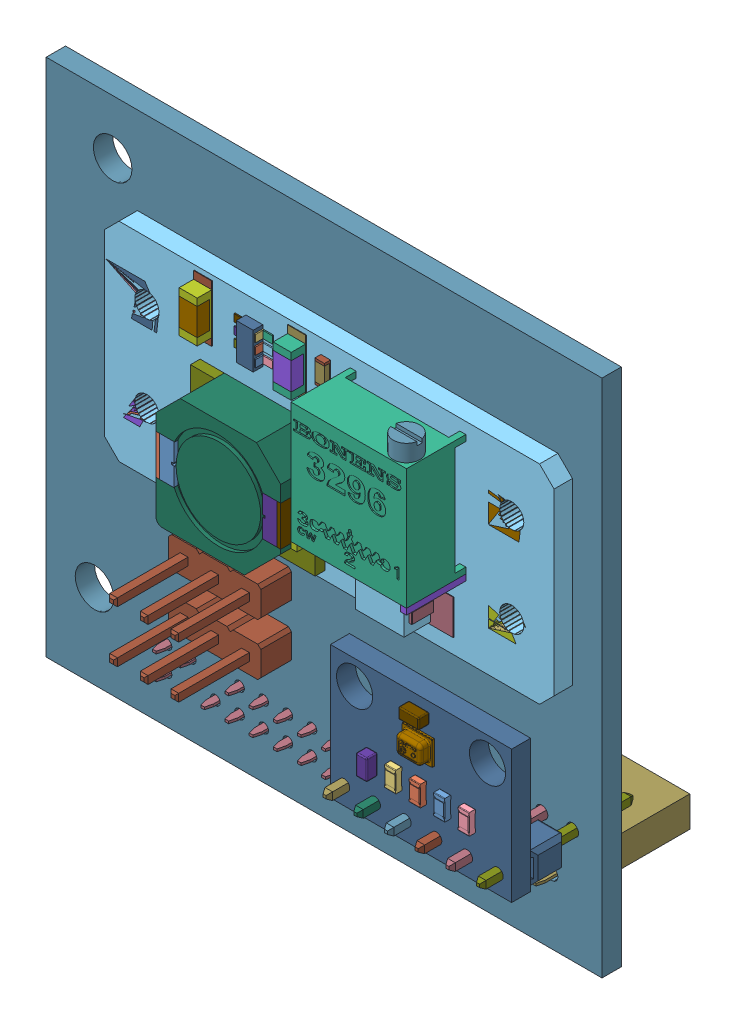
SolidWorks assembly IMUnav_H00_Addon, configuration Výchozí. Lengths in mm.
Overall size (46 43 18.74).
75 component instances, 68 part files, 0 mates.
Components (placement in the parent):
- MT3608 v3-1: MT3608 v3 [Výchozí] at (45.6 -22.4 3.65) x (-1 0 0) z (0 1 0) size (37.2 6.49 17.69)
  - MT3608 v3-1: MT3608 v3 [Výchozí] at origin size (5.34 1.58 3.22)
  - MT3608 v3_44-1: MT3608 v3_44 [Výchozí] at origin size (5.34 1.58 3.22)
  - MT3608 v3_28-1: MT3608 v3_28 [Výchozí] at origin size (5.34 1.58 3.22)
  - MT3608 v3_26-1: MT3608 v3_26 [Výchozí] at origin size (5.34 1.58 3.22)
  - MT3608 v3_13-1: MT3608 v3_13 [Výchozí] at origin size (37.2 1.52 17.23)
  - MT3608 v3_41-1: MT3608 v3_41 [Výchozí] at origin size (9.57 4.91 10)
  - MT3608 v3_11-1: MT3608 v3_11 [Výchozí] at origin size (5.34 1.5 3.22)
  - MT3608 v3_29-1: MT3608 v3_29 [Výchozí] at origin size (5.34 1.5 3.22)
  - MT3608 v3_42-1: MT3608 v3_42 [Výchozí] at origin size (5.34 1.5 3.22)
  - MT3608 v3_43-1: MT3608 v3_43 [Výchozí] at origin size (5.34 1.5 3.22)
  - MT3608 v3_15-1: MT3608 v3_15 [Výchozí] at origin size (1.5 0.05 4.7)
  - MT3608 v3_16-1: MT3608 v3_16 [Výchozí] at origin size (1.5 0.05 4.7)
  - MT3608 v3_14-1: MT3608 v3_14 [Výchozí] at origin size (7.73 1.85 2.9)
  - MT3608 v3_30-1: MT3608 v3_30 [Výchozí] at origin size (2.2 2.2 1.4)
  - MT3608 v3_39-1: MT3608 v3_39 [Výchozí] at origin size (10.32 3.65 10)
  - MT3608 v3_9-1: MT3608 v3_9 [Výchozí] at origin size (10.32 0.8 10)
  - MT3608 v3_10-1: MT3608 v3_10 [Výchozí] at origin size (1.2 0.3 3.3)
  - MT3608 v3_12-1: MT3608 v3_12 [Výchozí] at origin size (0.3 3.6 3.3)
  - MT3608 v3_31-1: MT3608 v3_31 [Výchozí] at origin size (1.2 0.3 3.3)
  - MT3608 v3_17-1: MT3608 v3_17 [Výchozí] at origin size (0.3 3.6 3.3)
  - MT3608 v3_8-1: MT3608 v3_8 [Výchozí] at origin size (1 0.1 3.3)
  - MT3608 v3_40-1: MT3608 v3_40 [Výchozí] at origin size (1 0.1 3.3)
  - MT3608 v3_27-1: MT3608 v3_27 [Výchozí] at origin size (4 2.2 2.5)
  - MT3608 v3_2-1: MT3608 v3_2 [Výchozí] at origin size (1.5 1.2 3.44)
  - MT3608 v3_33-1: MT3608 v3_33 [Výchozí] at origin size (1.5 1.2 3.44)
  - MT3608 v3_3-1: MT3608 v3_3 [Výchozí] at origin size (1.5 1 2.24)
  - MT3608 v3_18-1: MT3608 v3_18 [Výchozí] at origin size (1.5 1 2.24)
  - MT3608 v3_19-1: MT3608 v3_19 [Výchozí] at origin size (1.4 0.8 3)
  - MT3608 v3_22-1: MT3608 v3_22 [Výchozí] at origin size (0.8 0.5 1.9)
  - MT3608 v3_4-1: MT3608 v3_4 [Výchozí] at origin size (0.8 0.4 1.5)
  - MT3608 v3_35-1: MT3608 v3_35 [Výchozí] at origin size (0.1 0.7 0.6)
  - MT3608 v3_20-1: MT3608 v3_20 [Výchozí] at origin size (0.1 0.7 0.6)
  - MT3608 v3_34-1: MT3608 v3_34 [Výchozí] at origin size (0.1 0.7 0.6)
  - MT3608 v3_5-1: MT3608 v3_5 [Výchozí] at origin size (0.8 0.1 0.6)
  - MT3608 v3_6-1: MT3608 v3_6 [Výchozí] at origin size (0.8 0.1 0.6)
  - MT3608 v3_21-1: MT3608 v3_21 [Výchozí] at origin size (0.8 0.1 0.6)
  - MT3608 v3_7-1: MT3608 v3_7 [Výchozí] at origin size (0.1 0.7 0.6)
  - MT3608 v3_23-1: MT3608 v3_23 [Výchozí] at origin size (0.1 0.7 0.6)
  - MT3608 v3_37-1: MT3608 v3_37 [Výchozí] at origin size (0.1 0.7 0.6)
  - MT3608 v3_38-1: MT3608 v3_38 [Výchozí] at origin size (0.8 0.1 0.6)
  - MT3608 v3_36-1: MT3608 v3_36 [Výchozí] at origin size (0.8 0.1 0.6)
  - MT3608 v3_24-1: MT3608 v3_24 [Výchozí] at origin size (0.8 0.1 0.6)
  - MT3608 v3_25-1: MT3608 v3_25 [Výchozí] at origin size (0.5 4.91 0.5)
  - MT3608 v3_32-1: MT3608 v3_32 [Výchozí] at origin size (0.5 4.91 0.5)
- bmp280_module-1: bmp280_module [Výchozí] at (40.61 -33.473 30.65) x (0 -1 0) z (-1 0 0) size (11 12.7 15.24)
  - bmp280_module_Shrinkwrap-1: bmp280_module_Shrinkwrap [Výchozí] at origin size (2 1.64 2.5)
  - bmp280_module_Shrinkwrap_16-1: bmp280_module_Shrinkwrap_16 [Výchozí] at origin size (11 1.57 15)
  - bmp280_module_Shrinkwrap_10-1: bmp280_module_Shrinkwrap_10 [Výchozí] at origin size (0.63 12.7 0.63)
  - bmp280_module_Shrinkwrap_9-1: bmp280_module_Shrinkwrap_9 [Výchozí] at origin size (0.63 12.7 0.63)
  - bmp280_module_Shrinkwrap_2-1: bmp280_module_Shrinkwrap_2 [Výchozí] at origin size (0.63 12.7 0.63)
  - bmp280_module_Shrinkwrap_17-1: bmp280_module_Shrinkwrap_17 [Výchozí] at origin size (0.63 12.7 0.63)
  - bmp280_module_Shrinkwrap_5-1: bmp280_module_Shrinkwrap_5 [Výchozí] at origin size (0.63 12.7 0.63)
  - bmp280_module_Shrinkwrap_13-1: bmp280_module_Shrinkwrap_13 [Výchozí] at origin size (0.63 12.7 0.63)
  - bmp280_module_Shrinkwrap_12-1: bmp280_module_Shrinkwrap_12 [Výchozí] at origin size (1.7 0.9 0.9)
  - bmp280_module_Shrinkwrap_11-1: bmp280_module_Shrinkwrap_11 [Výchozí] at origin size (0.9 0.9 1.7)
  - bmp280_module_Shrinkwrap_19-1: bmp280_module_Shrinkwrap_19 [Výchozí] at origin size (1.7 0.55 0.9)
  - bmp280_module_Shrinkwrap_6-1: bmp280_module_Shrinkwrap_6 [Výchozí] at origin size (1.7 0.55 0.9)
  - bmp280_module_Shrinkwrap_7-1: bmp280_module_Shrinkwrap_7 [Výchozí] at origin size (1.7 0.55 0.9)
  - bmp280_module_Shrinkwrap_15-1: bmp280_module_Shrinkwrap_15 [Výchozí] at origin size (1.7 0.55 0.9)
  - bmp280_module_Shrinkwrap_4-1: bmp280_module_Shrinkwrap_4 [Výchozí] at origin size (2.54 2.8 2.54)
  - bmp280_module_Shrinkwrap_8-1: bmp280_module_Shrinkwrap_8 [Výchozí] at origin size (2.54 2.8 2.54)
  - bmp280_module_Shrinkwrap_14-1: bmp280_module_Shrinkwrap_14 [Výchozí] at origin size (2.54 2.8 2.54)
  - bmp280_module_Shrinkwrap_20-1: bmp280_module_Shrinkwrap_20 [Výchozí] at origin size (2.54 2.8 2.54)
  - bmp280_module_Shrinkwrap_3-1: bmp280_module_Shrinkwrap_3 [Výchozí] at origin size (2.54 2.8 2.54)
  - bmp280_module_Shrinkwrap_18-1: bmp280_module_Shrinkwrap_18 [Výchozí] at origin size (2.54 2.8 2.54)
- PinHeader_1x03_P2.54mm_Vertical-1: PinHeader_1x03_P2.54mm_Vertical [Výchozí] at (19.08 -32 1.65) x (0 -1 0) z (0 0 1) size (2.54 7.62 11.54)
  - PinHeader_1x03_P254mm_Vertical-1: PinHeader_1x03_P254mm_Vertical [Výchozí] at origin size (2.54 7.62 11.54)
- PinHeader_1x03_P2.54mm_Vertical-2: PinHeader_1x03_P2.54mm_Vertical [Výchozí] at (19.08 -27.7 1.65) x (0 -1 0) z (0 0 1) size (2.54 7.62 11.54)
  - PinHeader_1x03_P254mm_Vertical-1: PinHeader_1x03_P254mm_Vertical [Výchozí] at origin size (2.54 7.62 11.54)
- PinSocket_1x03_P2.54mm_Vertical-1: PinSocket_1x03_P2.54mm_Vertical [Výchozí] at (36.766 -37.592 -0.05) x (0 -1 0) z (0 0 -1) size (2.54 7.62 11.6)
  - PinSocket_1x03_P2.54mm_Vertical-1: PinSocket_1x03_P2.54mm_Vertical [Výchozí] at origin size (2.54 7.62 11.6)
- PinSocket_2x08_P2.00mm_Vertical-1: PinSocket_2x08_P2.00mm_Vertical [Výchozí] at (10 -39.08 -0.05) x (0 -1 0) z (0 0 -1) size (4 16 8.3)
  - PinSocket_2x08_P200mm_Vertical-1: PinSocket_2x08_P200mm_Vertical [Výchozí] at origin size (4 16 8.3)
- IMUnav_Gravi_Addon_PCB-1: IMUnav_Gravi_Addon_PCB [Výchozí] at origin size (46 43 1.6)
